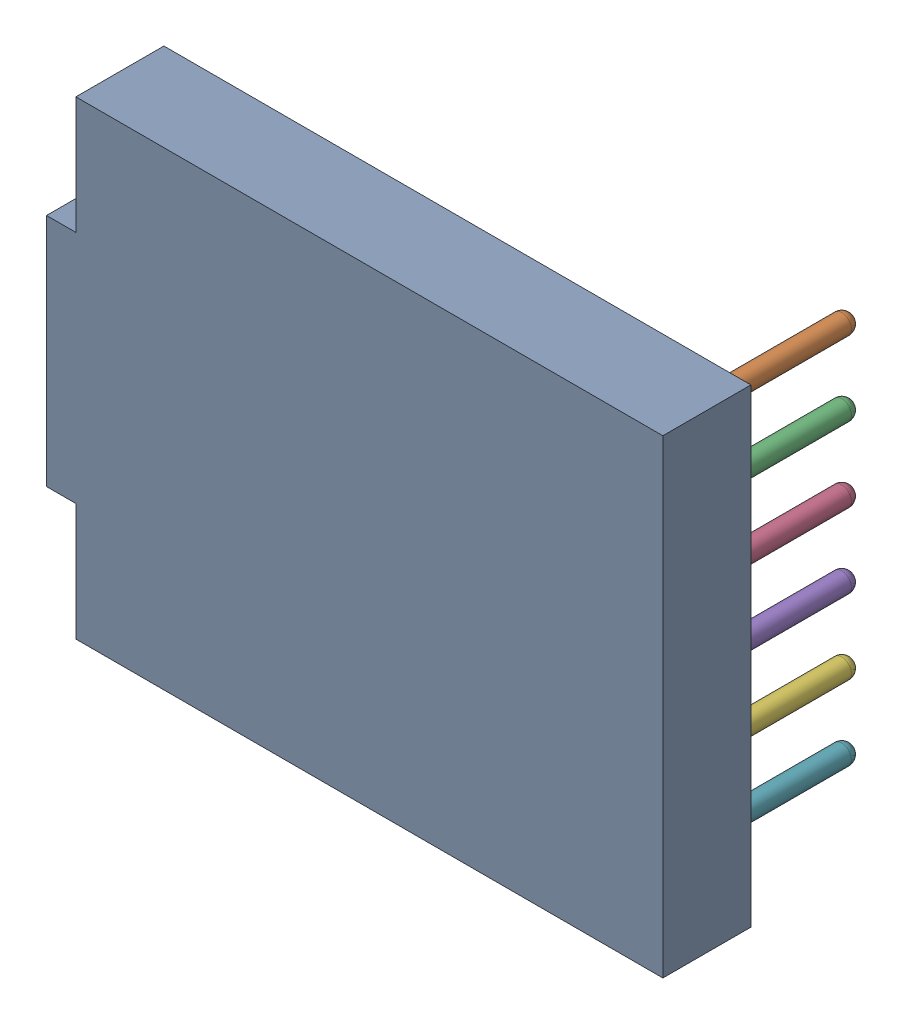
SolidWorks assembly U1, configuration Défaut. Lengths in mm.
Overall size (21 16 8.33).
8 component instances, 7 part files, 0 mates.
Components (placement in the parent):
- Open CASCADE STEP translator 6.8 1.15.1-1: Open CASCADE STEP translator 6.8 1.15.1 [Défaut] at origin size (21 16 8.33)
  - Body_1_8-1: Body_1_8 [Défaut] at origin size (21 16 3)
  - Pin_1_5-1: Pin_1_5 [Défaut] x (0 -1 0) z (0 0 1) size (0.66 0.66 7.16)
  - Pin_2_5-1: Pin_2_5 [Défaut] at (2.54 -2.54 0) x (0 -1 0) z (0 0 1) size (0.66 0.66 7.16)
  - Pin_3_3-1: Pin_3_3 [Défaut] at (5.08 -5.08 0) x (0 -1 0) z (0 0 1) size (0.66 0.66 7.16)
  - Pin_4_2-1: Pin_4_2 [Défaut] at (7.62 -7.62 0) x (0 -1 0) z (0 0 1) size (0.66 0.66 7.16)
  - Pin_5_2-1: Pin_5_2 [Défaut] at (10.16 -10.16 0) x (0 -1 0) z (0 0 1) size (0.66 0.66 7.16)
  - Pin_6_2-1: Pin_6_2 [Défaut] at (12.7 -12.7 0) x (0 -1 0) z (0 0 1) size (0.66 0.66 7.16)
